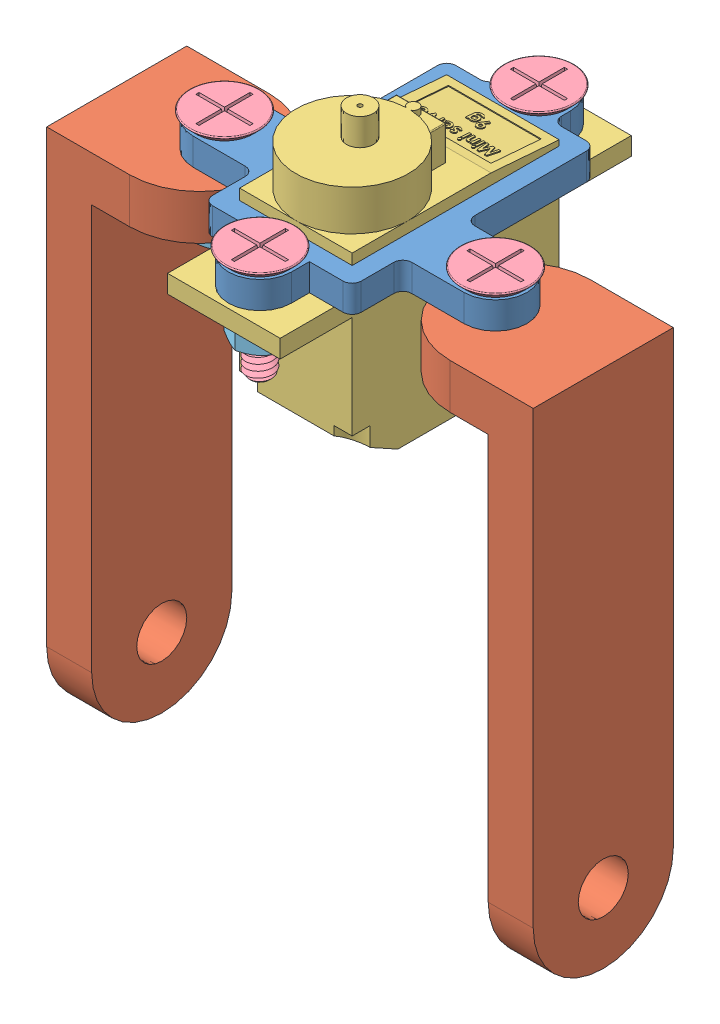
SolidWorks assembly Assem5, configuration Default. Lengths in mm.
Overall size (54.1 69.48 39).
12 component instances, 5 part files, 29 mates.
Components (placement in the parent):
- part6-1: part6 [Default] at origin size (37.1 3 38)
- part5-1: part5 [Default] at (-27.05 -50 -0.03) x (0 1 0) z (1 0 0) size (57.78 15.56 17)
- part5-2: part5 [Default] at (27.05 -50 0.03) x (0 1 0) z (-1 0 0) size (57.78 15.56 17)
- MiniServo1-1: MiniServo1 [Default] at (0 -17.2 -4.38) x (0 0 -1) z (1 0 0) size (39 28.9 12.5)
- straf3_dolg10-1: straf3_dolg10 [Default] at (-15.05 1.35 0) size (7.72 12.84 7.72)
- straf3_dolg10-2: straf3_dolg10 [Default] at (0 1.35 -19.88) size (7.72 12.84 7.72)
- straf3_dolg10-3: straf3_dolg10 [Default] at (0 1.35 11.12) size (7.72 12.84 7.72)
- straf3_dolg10-4: straf3_dolg10 [Default] at (15.05 1.35 0) size (7.72 12.84 7.72)
- navrtka3-1: navrtka3 [Default] at (15.05 -6.5 0) x (1 0 0) z (0 -1 0) size (5.57 5.77 3)
- navrtka3-2: navrtka3 [Default] at (0 -3.5 11.12) x (1 0 0) z (0 1 0) size (5.57 5.77 3)
- navrtka3-3: navrtka3 [Default] at (0 -3.5 -19.88) x (1 0 0) z (0 1 0) size (5.57 5.77 3)
- navrtka3-4: navrtka3 [Default] at (-15.05 -6.5 0) x (1 0 0) z (0 -1 0) size (5.57 5.77 3)
Mates (geometry in assembly coordinates):
- Concentric1: concentric anti-aligned: cylinder of part6-1 through (-15.05 3 0) axis (0 1 0) radius 1.5; cylinder of part5-1 through (-15.05 -5 0) axis (0 -1 0) radius 1.5
- Coincident1: coincident anti-aligned: plane of part6-1 through (0 0 0) normal (0 -1 0); plane of part5-1 through (-22.05 0 -0.03) normal (0 1 0)
- Concentric2: concentric anti-aligned: cylinder of part6-1 through (15.05 3 0) axis (0 1 0) radius 1.5; cylinder of part5-2 through (15.05 -5 0) axis (0 -1 0) radius 1.5
- Coincident2: coincident anti-aligned: plane of part6-1 through (0 0 0) normal (0 -1 0); plane of part5-2 through (22.05 0 0.03) normal (0 1 0)
- Parallel1: parallel aligned: plane of part6-1 through (-8.25 3 0) normal (-1 0 0); plane of part5-1 through (-27.05 -50 -0.03) normal (-1 0 0)
- Parallel2: parallel aligned: plane of part6-1 through (8.25 3 0) normal (1 0 0); plane of part5-2 through (27.05 -50 0.03) normal (1 0 0)
- Concentric3: concentric aligned: cylinder of part6-1 through (0 3 11.12) axis (0 1 0) radius 1.5; cylinder of MiniServo1-1 through (0 0 11.12) axis (0 1 0) radius 1.5
- Concentric4: concentric aligned: cylinder of part6-1 through (0 3 -19.88) axis (0 1 0) radius 1.5; cylinder of MiniServo1-1 through (0 0 -19.88) axis (0 1 0) radius 1.5
- Coincident5: coincident anti-aligned: plane of part6-1 through (0 0 0) normal (0 -1 0); plane of MiniServo1-1 through (0 0 -4.38) normal (0 1 0)
- Coincident6: coincident aligned: cone of part6-1 through (-15.05 3 0) axis (0 -1 0); cone of straf3_dolg10-1 through (-15.05 1.35 0) axis (0 -1 0)
- Coincident7: coincident aligned: cone of part6-1 through (0 3 -19.88) axis (0 -1 0); cone of straf3_dolg10-2 through (0 1.35 -19.88) axis (0 -1 0)
- Coincident8: coincident aligned: cone of part6-1 through (0 3 11.12) axis (0 -1 0); cone of straf3_dolg10-3 through (0 1.35 11.12) axis (0 -1 0)
- Coincident9: coincident aligned: cone of part6-1 through (15.05 3 0) axis (0 -1 0); cone of straf3_dolg10-4 through (15.05 1.35 0) axis (0 -1 0)
- Concentric9: concentric anti-aligned: cylinder of part5-1 through (-15.05 -5 0) axis (0 -1 0) radius 1.5; circle of navrtka3-4
- Coincident10: coincident anti-aligned: plane of part5-1 through (-10.05 -5 7.75) normal (0 -1 0); plane of navrtka3-4 through (-15.05 -5 0) normal (0 1 0)
- Concentric10: concentric anti-aligned: cylinder of part5-2 through (15.05 -5 0) axis (0 -1 0) radius 1.5; circle of navrtka3-1
- Coincident11: coincident anti-aligned: plane of part5-2 through (10.05 -5 -7.75) normal (0 -1 0); plane of navrtka3-1 through (15.05 -5 0) normal (0 1 0)
- Concentric11: concentric anti-aligned: cylinder of MiniServo1-1 through (0 0 11.12) axis (0 1 0) radius 1.5; circle of navrtka3-2
- Coincident12: coincident anti-aligned: plane of MiniServo1-1 through (0 -2 -4.38) normal (0 -1 0); plane of navrtka3-2 through (0 -2 11.12) normal (0 1 0)
- Concentric12: concentric anti-aligned: cylinder of MiniServo1-1 through (0 0 -19.88) axis (0 1 0) radius 1.5; circle of navrtka3-3
- Coincident13: coincident anti-aligned: plane of MiniServo1-1 through (0 -2 -4.38) normal (0 -1 0); plane of navrtka3-3 through (0 -2 -19.88) normal (0 1 0)
- Parallel5: parallel aligned: plane of straf3_dolg10-1 through (-15.05 1.35 0) normal (0 0 1); plane of assembly through (0 0 0) normal (0 0 1)
- Parallel6: parallel aligned: plane of straf3_dolg10-2 through (0 1.35 -19.88) normal (0 0 1); plane of assembly through (0 0 0) normal (0 0 1)
- Parallel7: parallel aligned: plane of straf3_dolg10-4 through (15.05 1.35 0) normal (0 0 1); plane of assembly through (0 0 0) normal (0 0 1)
- Coincident19: coincident aligned: plane of navrtka3-1 through (15.05 -6.5 0) normal (0 0 1); plane of assembly through (0 0 0) normal (0 0 1)
- Parallel8: parallel anti-aligned: plane of navrtka3-2 through (0 -3.5 11.12) normal (0 0 -1); plane of assembly through (0 0 0) normal (0 0 1)
- Parallel9: parallel anti-aligned: plane of navrtka3-3 through (0 -3.5 -19.88) normal (0 0 -1); plane of assembly through (0 0 0) normal (0 0 1)
- Parallel10: parallel aligned: plane of navrtka3-4 through (-15.05 -6.5 0) normal (0 0 1); plane of assembly through (0 0 0) normal (0 0 1)
- Parallel11: parallel aligned: plane of straf3_dolg10-3 through (0 1.35 11.12) normal (0 0 1); plane of assembly through (0 0 0) normal (0 0 1)
